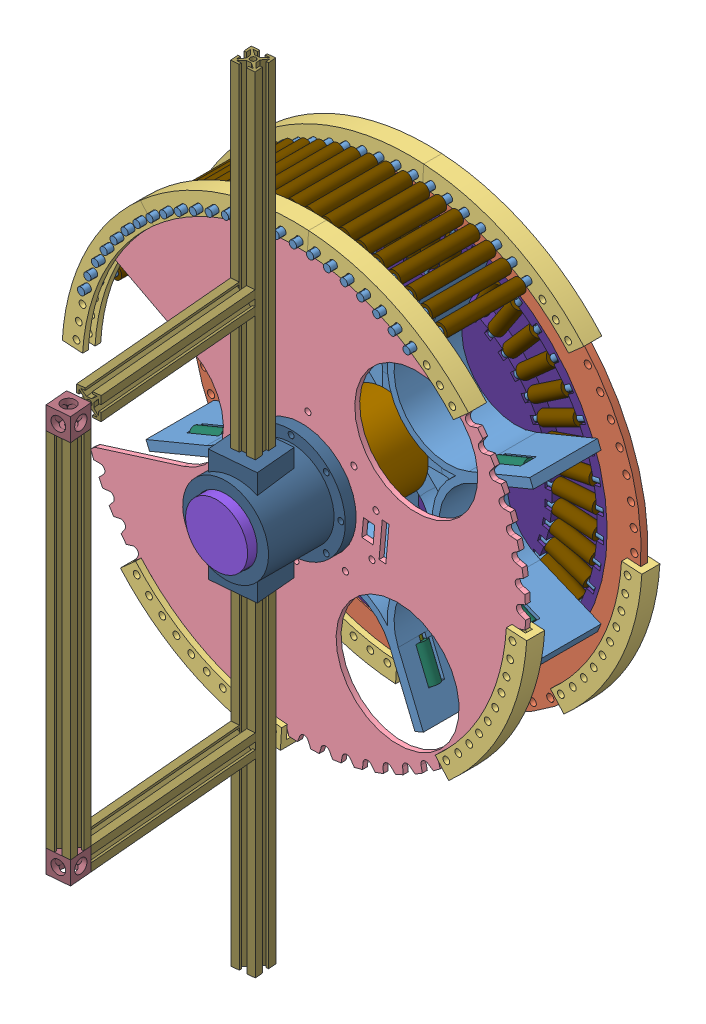
SolidWorks assembly DistributorGrabberAssembly, configuration Default. Lengths in mm.
Overall size (258.72 347.5 175.42).
192 component instances, 20 part files, 82 mates.
Components (placement in the parent):
- DistributorGrabberMainPiece-1: DistributorGrabberMainPiece [Default] at (8.177 183.1473 -41.1858) size (171.5 171.5 30)
- DistributorGrabberStaticCylinder-1: DistributorGrabberStaticCylinder [Default] at (8.177 183.1473 -47.6858) x (-0.932546 -0.361051 0) z (-0.361051 0.932546 0) size (200 3 200)
- ExternalBlockingPiece-1: ExternalBlockingPiece [Default] at (8.177 183.1473 -46.1858) x (-0.748631 -0.662987 0) z (-0.662987 0.748631 0) size (36.53 8 72.83)
- DistributorGrabberStaticTopCylinder-1: DistributorGrabberStaticTopCylinder [Default] at (8.177 183.1473 5.5142) x (-0.088346 -0.99609 0) z (0 0 -1) size (198 187.74 2.2)
- Bearing22mmx7mm-1: Bearing22mmx7mm [Défaut] at (8.177 183.1473 -48.191) x (0 0 -1) z (0.998937 0.04609 0) size (7.02 22 22)
  - AST_Bearings_627H1-1: AST_Bearings_627H1 [Défaut] at origin size (7.02 12.2 12.2)
  - AST_Bearings_627H2-1: AST_Bearings_627H2 [Défaut] at origin size (7.02 22 22)
  - AST_Bearings_627H3-1: AST_Bearings_627H3 [Défaut] at origin size (4.12 17.82 18.09)
- MFA940D1001-1: MFA940D1001 [Default] at (8.177 183.1473 5.3142) x (0 0 -1) z (0 1 0) size (89.5 32 32)
- CentralMotorSupportPart1-1: CentralMotorSupportPart1 [Default] at (8.177 183.1473 5.3142) x (0.707107 -0.707107 0) z (0.707107 0.707107 0) size (48.4 36.5 48.4)
- CentralMotorSupportPart2-1: CentralMotorSupportPart2 [Default] at (8.177 183.1473 5.3142) x (-1 0 0) z (0 1 0) size (48 34 50)
- MotorDistributorGrabberRotor-1: MotorDistributorGrabberRotor [Default] at (8.177 183.1473 -44.1858) size (38 38 20)
- Makerbeam50-1000mm-1: Makerbeam50-1000mm [160mm] at (7.3054 169.3973 26.1553) x (0.996195 0 -0.087156) z (0 -1 0) size (10 10 160)
- Makerbeam50-1000mm-2: Makerbeam50-1000mm [160mm] at (7.3141 196.8973 26.2549) x (-0.996195 0 0.087156) z (0 1 0) size (10 10 160)
- Makerbeam50-1000mm-3: Makerbeam50-1000mm [80mm] at (14.7136 98.3973 110.8319) x (-0.996195 0 0.087156) z (-0.087156 0 -0.996195) size (10 10 80)
- Makerbeam50-1000mm-4: Makerbeam50-1000mm [160mm] at (15.1494 103.3973 115.8128) x (0.996195 0 -0.087156) z (0 1 0) size (10 10 160)
- Makerbeam50-1000mm-5: Makerbeam50-1000mm [75mm] at (7.7499 268.3973 31.2359) x (0.996195 0 -0.087156) z (0.087156 0 0.996195) size (10 10 75)
- MakerBeam-cube-1: MakerBeam-cube [Default] at (15.1494 103.3973 115.8128) x (0.996195 0 -0.087156) z (0 -1 0) size (10 10 10)
- MakerBeam-cube-2: MakerBeam-cube [Default] at (14.7136 268.3973 110.8319) x (0.996195 0 -0.087156) z (0.087156 0 0.996195) size (10 10 10)
- Ball2018-6: Ball2018 [Default] at (-37.5478 134.0815 -22.4358) x (0.994403 0.003773 -0.105582) z (0.105601 -0.005362 0.994394) size (44.5 44.5 44.5)
- RotationCylinder15mm-1: RotationCylinder15mm [Default] at (-65.7215 213.7327 -21.6858) x (0.150802 0.364068 -0.919083) z (0.92388 -0.382683 0) size (6 6 15)
- DistributorGrabberMainPieceThreadedScrew-1: DistributorGrabberMainPieceThreadedScrew [Default] at (-49.0916 206.8444 -21.6858) x (-0.366115 -0.88388 0.29106) z (-0.92388 0.382683 0) size (2.5 2.5 20)
- RotationCylinder15mm-2: RotationCylinder15mm [Default] at (-65.7043 152.5203 -21.6858) x (-0.150802 0.364068 -0.919083) z (0.92388 0.382683 0) size (6 6 15)
- RotationCylinder15mm-3: RotationCylinder15mm [Default] at (-22.4084 109.2488 -21.6858) x (-0.364068 0.150802 -0.919083) z (0.382683 0.92388 0) size (6 6 15)
- RotationCylinder15mm-4: RotationCylinder15mm [Default] at (38.8039 109.266 -21.6858) x (-0.364068 -0.150802 -0.919083) z (-0.382683 0.92388 0) size (6 6 15)
- RotationCylinder15mm-5: RotationCylinder15mm [Default] at (82.0754 152.5619 -21.6858) x (-0.150802 -0.364068 -0.919083) z (-0.92388 0.382683 0) size (6 6 15)
- RotationCylinder15mm-6: RotationCylinder15mm [Default] at (82.0582 213.7742 -21.6858) x (0.150802 -0.364068 -0.919083) z (-0.92388 -0.382683 0) size (6 6 15)
- RotationCylinder15mm-7: RotationCylinder15mm [Default] at (38.7624 257.0457 -21.6858) x (0.364068 -0.150802 -0.919083) z (-0.382683 -0.92388 0) size (6 6 15)
- RotationCylinder15mm-8: RotationCylinder15mm [Default] at (-22.45 257.0285 -21.6858) x (0.364068 0.150802 -0.919083) z (0.382683 -0.92388 0) size (6 6 15)
- DistributorGrabberMainPieceThreadedScrew-2: DistributorGrabberMainPieceThreadedScrew [Default] at (-49.0744 159.4086 -21.6858) x (0.366115 -0.88388 0.29106) z (-0.92388 -0.382683 0) size (2.5 2.5 20)
- DistributorGrabberMainPieceThreadedScrew-3: DistributorGrabberMainPieceThreadedScrew [Default] at (-15.5201 125.8787 -21.6858) x (0.88388 -0.366115 0.29106) z (-0.382683 -0.92388 0) size (2.5 2.5 20)
- DistributorGrabberMainPieceThreadedScrew-4: DistributorGrabberMainPieceThreadedScrew [Default] at (31.9156 125.8959 -21.6858) x (0.88388 0.366115 0.29106) z (0.382683 -0.92388 0) size (2.5 2.5 20)
- DistributorGrabberMainPieceThreadedScrew-5: DistributorGrabberMainPieceThreadedScrew [Default] at (65.4455 159.4502 -21.6858) x (0.366115 0.88388 0.29106) z (0.92388 -0.382683 0) size (2.5 2.5 20)
- DistributorGrabberMainPieceThreadedScrew-6: DistributorGrabberMainPieceThreadedScrew [Default] at (65.4283 206.8859 -21.6858) x (-0.366115 0.88388 0.29106) z (0.92388 0.382683 0) size (2.5 2.5 20)
- DistributorGrabberMainPieceThreadedScrew-7: DistributorGrabberMainPieceThreadedScrew [Default] at (31.8741 240.4159 -21.6858) x (-0.88388 0.366115 0.29106) z (0.382683 0.92388 0) size (2.5 2.5 20)
- DistributorGrabberMainPieceThreadedScrew-8: DistributorGrabberMainPieceThreadedScrew [Default] at (-15.5617 240.3987 -21.6858) x (-0.88388 -0.366115 0.29106) z (-0.382683 0.92388 0) size (2.5 2.5 20)
- DistributorRollingBearSupportWithCylinderSupportAssembly-1: DistributorRollingBearSupportWithCylinderSupportAssembly [Default] at (-21.5454 144.6098 -52.8042) x (-0.894404 -0.447259 0) z (-0.447259 0.894404 0) size (186 10 186)
  - DistributorRollingBearSupportWithCylinderSupport-1: DistributorRollingBearSupportWithCylinderSupport [Default] at (-43.82 -1.3816 21.1745) size (186 9 186)
  - BlockingCylinder-2: BlockingCylinder [18mm] at (35.18 5.6184 21.1745) x (0 0 1) z (-1 0 0) size (6 6 18)
  - BlockingCylinderSupport-1: BlockingCylinderSupport [25mm] at (13.68 5.6184 21.1745) x (0 0 -1) z (1 0 0) size (3.2 3.2 25)
  - BlockingCylinder-3: BlockingCylinder [18mm] at (34.5041 5.6184 31.4861) x (-0.130526 0 0.991445) z (-0.991445 0 -0.130526) size (6 6 18)
  - BlockingCylinder-4: BlockingCylinder [18mm] at (32.4881 5.6184 41.6212) x (-0.258819 0 0.965926) z (-0.965926 0 -0.258819) size (6 6 18)
  - BlockingCylinder-5: BlockingCylinder [18mm] at (29.1665 5.6184 51.4065) x (-0.382683 0 0.92388) z (-0.92388 0 -0.382683) size (6 6 18)
  - BlockingCylinder-6: BlockingCylinder [18mm] at (24.596 5.6184 60.6745) x (-0.5 0 0.866025) z (-0.866025 0 -0.5) size (6 6 18)
  - BlockingCylinder-7: BlockingCylinder [18mm] at (18.8549 5.6184 69.2667) x (-0.608761 0 0.793353) z (-0.793353 0 -0.608761) size (6 6 18)
  - BlockingCylinder-8: BlockingCylinder [18mm] at (12.0414 5.6184 77.0359) x (-0.707107 0 0.707107) z (-0.707107 0 -0.707107) size (6 6 18)
  - BlockingCylinder-9: BlockingCylinder [18mm] at (4.2721 5.6184 83.8494) x (-0.793353 0 0.608761) z (-0.608761 0 -0.793353) size (6 6 18)
  - BlockingCylinder-10: BlockingCylinder [18mm] at (-4.32 5.6184 89.5905) x (-0.866025 0 0.5) z (-0.5 0 -0.866025) size (6 6 18)
  - BlockingCylinder-11: BlockingCylinder [18mm] at (-13.588 5.6184 94.161) x (-0.92388 0 0.382683) z (-0.382683 0 -0.92388) size (6 6 18)
  - BlockingCylinder-12: BlockingCylinder [18mm] at (-23.3733 5.6184 97.4826) x (-0.965926 0 0.258819) z (-0.258819 0 -0.965926) size (6 6 18)
  - BlockingCylinder-13: BlockingCylinder [18mm] at (-33.5085 5.6184 99.4987) x (-0.991445 0 0.130526) z (-0.130526 0 -0.991445) size (6 6 18)
  - BlockingCylinder-14: BlockingCylinder [18mm] at (-43.82 5.6184 100.1745) x (-1 0 0) z (0 0 -1) size (6 6 18)
  - BlockingCylinder-15: BlockingCylinder [18mm] at (-54.1316 5.6184 99.4987) x (-0.991445 0 -0.130526) z (0.130526 0 -0.991445) size (6 6 18)
  - BlockingCylinder-16: BlockingCylinder [18mm] at (-64.2667 5.6184 97.4826) x (-0.965926 0 -0.258819) z (0.258819 0 -0.965926) size (6 6 18)
  - BlockingCylinder-17: BlockingCylinder [18mm] at (-74.052 5.6184 94.161) x (-0.92388 0 -0.382683) z (0.382683 0 -0.92388) size (6 6 18)
  - BlockingCylinder-18: BlockingCylinder [18mm] at (-83.32 5.6184 89.5905) x (-0.866025 0 -0.5) z (0.5 0 -0.866025) size (6 6 18)
  - BlockingCylinder-19: BlockingCylinder [18mm] at (-91.9122 5.6184 83.8494) x (-0.793353 0 -0.608761) z (0.608761 0 -0.793353) size (6 6 18)
  - BlockingCylinder-20: BlockingCylinder [18mm] at (-99.6815 5.6184 77.0359) x (-0.707107 0 -0.707107) z (0.707107 0 -0.707107) size (6 6 18)
  - BlockingCylinder-21: BlockingCylinder [18mm] at (-106.4949 5.6184 69.2667) x (-0.608761 0 -0.793353) z (0.793353 0 -0.608761) size (6 6 18)
  - BlockingCylinder-22: BlockingCylinder [18mm] at (-112.236 5.6184 60.6745) x (-0.5 0 -0.866025) z (0.866025 0 -0.5) size (6 6 18)
  - BlockingCylinder-23: BlockingCylinder [18mm] at (-116.8065 5.6184 51.4065) x (-0.382683 0 -0.92388) z (0.92388 0 -0.382683) size (6 6 18)
  - BlockingCylinder-24: BlockingCylinder [18mm] at (-120.1282 5.6184 41.6212) x (-0.258819 0 -0.965926) z (0.965926 0 -0.258819) size (6 6 18)
  - BlockingCylinder-25: BlockingCylinder [18mm] at (-122.1442 5.6184 31.4861) x (-0.130526 0 -0.991445) z (0.991445 0 -0.130526) size (6 6 18)
  - BlockingCylinder-26: BlockingCylinder [18mm] at (-122.82 5.6184 21.1745) x (0 0 -1) z (1 0 0) size (6 6 18)
  - BlockingCylinder-27: BlockingCylinder [18mm] at (-122.1442 5.6184 10.8629) x (0.130526 0 -0.991445) z (0.991445 0 0.130526) size (6 6 18)
  - BlockingCylinder-28: BlockingCylinder [18mm] at (-120.1282 5.6184 0.7278) x (0.258819 0 -0.965926) z (0.965926 0 0.258819) size (6 6 18)
  - BlockingCylinder-29: BlockingCylinder [18mm] at (-116.8065 5.6184 -9.0575) x (0.382683 0 -0.92388) z (0.92388 0 0.382683) size (6 6 18)
  - BlockingCylinder-30: BlockingCylinder [18mm] at (-112.236 5.6184 -18.3255) x (0.5 0 -0.866025) z (0.866025 0 0.5) size (6 6 18)
  - BlockingCylinder-31: BlockingCylinder [18mm] at (-106.4949 5.6184 -26.9176) x (0.608761 0 -0.793353) z (0.793353 0 0.608761) size (6 6 18)
  - BlockingCylinder-32: BlockingCylinder [18mm] at (-99.6815 5.6184 -34.6869) x (0.707107 0 -0.707107) z (0.707107 0 0.707107) size (6 6 18)
  - BlockingCylinder-33: BlockingCylinder [18mm] at (-91.9122 5.6184 -41.5004) x (0.793353 0 -0.608761) z (0.608761 0 0.793353) size (6 6 18)
  - BlockingCylinder-34: BlockingCylinder [18mm] at (-83.32 5.6184 -47.2415) x (0.866025 0 -0.5) z (0.5 0 0.866025) size (6 6 18)
  - BlockingCylinder-35: BlockingCylinder [18mm] at (-74.052 5.6184 -51.812) x (0.92388 0 -0.382683) z (0.382683 0 0.92388) size (6 6 18)
  - BlockingCylinder-36: BlockingCylinder [18mm] at (-64.2667 5.6184 -55.1336) x (0.965926 0 -0.258819) z (0.258819 0 0.965926) size (6 6 18)
  - BlockingCylinder-37: BlockingCylinder [18mm] at (-54.1316 5.6184 -57.1496) x (0.991445 0 -0.130526) z (0.130526 0 0.991445) size (6 6 18)
  - BlockingCylinder-38: BlockingCylinder [18mm] at (-43.82 5.6184 -57.8255) size (6 6 18)
  - BlockingCylinder-39: BlockingCylinder [18mm] at (-33.5085 5.6184 -57.1496) x (0.991445 0 0.130526) z (-0.130526 0 0.991445) size (6 6 18)
  - BlockingCylinder-40: BlockingCylinder [18mm] at (-23.3733 5.6184 -55.1336) x (0.965926 0 0.258819) z (-0.258819 0 0.965926) size (6 6 18)
  - BlockingCylinder-41: BlockingCylinder [18mm] at (-13.588 5.6184 -51.812) x (0.92388 0 0.382683) z (-0.382683 0 0.92388) size (6 6 18)
  - BlockingCylinder-42: BlockingCylinder [18mm] at (-4.32 5.6184 -47.2415) x (0.866025 0 0.5) z (-0.5 0 0.866025) size (6 6 18)
  - BlockingCylinder-43: BlockingCylinder [18mm] at (4.2721 5.6184 -41.5004) x (0.793353 0 0.608761) z (-0.608761 0 0.793353) size (6 6 18)
  - BlockingCylinder-44: BlockingCylinder [18mm] at (12.0414 5.6184 -34.6869) x (0.707107 0 0.707107) z (-0.707107 0 0.707107) size (6 6 18)
  - BlockingCylinder-45: BlockingCylinder [18mm] at (18.8549 5.6184 -26.9176) x (0.608761 0 0.793353) z (-0.793353 0 0.608761) size (6 6 18)
  - BlockingCylinder-46: BlockingCylinder [18mm] at (24.596 5.6184 -18.3255) x (0.5 0 0.866025) z (-0.866025 0 0.5) size (6 6 18)
  - BlockingCylinder-47: BlockingCylinder [18mm] at (29.1665 5.6184 -9.0575) x (0.382683 0 0.92388) z (-0.92388 0 0.382683) size (6 6 18)
  - BlockingCylinder-48: BlockingCylinder [18mm] at (32.4881 5.6184 0.7278) x (0.258819 0 0.965926) z (-0.965926 0 0.258819) size (6 6 18)
  - BlockingCylinder-49: BlockingCylinder [18mm] at (34.5041 5.6184 10.8629) x (0.130526 0 0.991445) z (-0.991445 0 0.130526) size (6 6 18)
  - BlockingCylinderSupport-2: BlockingCylinderSupport [25mm] at (13.1881 5.6184 28.6798) x (0.130526 0 -0.991445) z (0.991445 0 0.130526) size (3.2 3.2 25)
  - BlockingCylinderSupport-3: BlockingCylinderSupport [25mm] at (11.7207 5.6184 36.0566) x (0.258819 0 -0.965926) z (0.965926 0 0.258819) size (3.2 3.2 25)
  - BlockingCylinderSupport-4: BlockingCylinderSupport [25mm] at (9.303 5.6184 43.1788) x (0.382683 0 -0.92388) z (0.92388 0 0.382683) size (3.2 3.2 25)
  - BlockingCylinderSupport-5: BlockingCylinderSupport [25mm] at (5.9764 5.6184 49.9245) x (0.5 0 -0.866025) z (0.866025 0 0.5) size (3.2 3.2 25)
  - BlockingCylinderSupport-6: BlockingCylinderSupport [25mm] at (1.7978 5.6184 56.1783) x (0.608761 0 -0.793353) z (0.793353 0 0.608761) size (3.2 3.2 25)
  - BlockingCylinderSupport-7: BlockingCylinderSupport [25mm] at (-3.1614 5.6184 61.8331) x (0.707107 0 -0.707107) z (0.707107 0 0.707107) size (3.2 3.2 25)
  - BlockingCylinderSupport-8: BlockingCylinderSupport [25mm] at (-8.8162 5.6184 66.7923) x (0.793353 0 -0.608761) z (0.608761 0 0.793353) size (3.2 3.2 25)
  - BlockingCylinderSupport-9: BlockingCylinderSupport [25mm] at (-15.07 5.6184 70.971) x (0.866025 0 -0.5) z (0.5 0 0.866025) size (3.2 3.2 25)
  - BlockingCylinderSupport-10: BlockingCylinderSupport [25mm] at (-21.8157 5.6184 74.2976) x (0.92388 0 -0.382683) z (0.382683 0 0.92388) size (3.2 3.2 25)
  - BlockingCylinderSupport-11: BlockingCylinderSupport [25mm] at (-28.9379 5.6184 76.7152) x (0.965926 0 -0.258819) z (0.258819 0 0.965926) size (3.2 3.2 25)
  - BlockingCylinderSupport-12: BlockingCylinderSupport [25mm] at (-36.3148 5.6184 78.1826) x (0.991445 0 -0.130526) z (0.130526 0 0.991445) size (3.2 3.2 25)
  - BlockingCylinderSupport-13: BlockingCylinderSupport [25mm] at (-43.82 5.6184 78.6745) size (3.2 3.2 25)
  - BlockingCylinderSupport-14: BlockingCylinderSupport [25mm] at (-51.3253 5.6184 78.1826) x (0.991445 0 0.130526) z (-0.130526 0 0.991445) size (3.2 3.2 25)
  - BlockingCylinderSupport-15: BlockingCylinderSupport [25mm] at (-58.7021 5.6184 76.7152) x (0.965926 0 0.258819) z (-0.258819 0 0.965926) size (3.2 3.2 25)
  - BlockingCylinderSupport-16: BlockingCylinderSupport [25mm] at (-65.8243 5.6184 74.2976) x (0.92388 0 0.382683) z (-0.382683 0 0.92388) size (3.2 3.2 25)
  - BlockingCylinderSupport-17: BlockingCylinderSupport [25mm] at (-72.57 5.6184 70.971) x (0.866025 0 0.5) z (-0.5 0 0.866025) size (3.2 3.2 25)
  - BlockingCylinderSupport-18: BlockingCylinderSupport [25mm] at (-78.8238 5.6184 66.7923) x (0.793353 0 0.608761) z (-0.608761 0 0.793353) size (3.2 3.2 25)
  - BlockingCylinderSupport-19: BlockingCylinderSupport [25mm] at (-84.4787 5.6184 61.8331) x (0.707107 0 0.707107) z (-0.707107 0 0.707107) size (3.2 3.2 25)
  - BlockingCylinderSupport-20: BlockingCylinderSupport [25mm] at (-89.4378 5.6184 56.1783) x (0.608761 0 0.793353) z (-0.793353 0 0.608761) size (3.2 3.2 25)
  - BlockingCylinderSupport-21: BlockingCylinderSupport [25mm] at (-93.6165 5.6184 49.9245) x (0.5 0 0.866025) z (-0.866025 0 0.5) size (3.2 3.2 25)
  - BlockingCylinderSupport-22: BlockingCylinderSupport [25mm] at (-96.9431 5.6184 43.1788) x (0.382683 0 0.92388) z (-0.92388 0 0.382683) size (3.2 3.2 25)
  - BlockingCylinderSupport-23: BlockingCylinderSupport [25mm] at (-99.3608 5.6184 36.0566) x (0.258819 0 0.965926) z (-0.965926 0 0.258819) size (3.2 3.2 25)
  - BlockingCylinderSupport-24: BlockingCylinderSupport [25mm] at (-100.8281 5.6184 28.6798) x (0.130526 0 0.991445) z (-0.991445 0 0.130526) size (3.2 3.2 25)
  - BlockingCylinderSupport-25: BlockingCylinderSupport [25mm] at (-101.32 5.6184 21.1745) x (0 0 1) z (-1 0 0) size (3.2 3.2 25)
  - BlockingCylinderSupport-26: BlockingCylinderSupport [25mm] at (-100.8281 5.6184 13.6693) x (-0.130526 0 0.991445) z (-0.991445 0 -0.130526) size (3.2 3.2 25)
  - BlockingCylinderSupport-27: BlockingCylinderSupport [25mm] at (-99.3608 5.6184 6.2924) x (-0.258819 0 0.965926) z (-0.965926 0 -0.258819) size (3.2 3.2 25)
  - BlockingCylinderSupport-28: BlockingCylinderSupport [25mm] at (-96.9431 5.6184 -0.8298) x (-0.382683 0 0.92388) z (-0.92388 0 -0.382683) size (3.2 3.2 25)
  - BlockingCylinderSupport-29: BlockingCylinderSupport [25mm] at (-93.6165 5.6184 -7.5755) x (-0.5 0 0.866025) z (-0.866025 0 -0.5) size (3.2 3.2 25)
  - BlockingCylinderSupport-30: BlockingCylinderSupport [25mm] at (-89.4378 5.6184 -13.8293) x (-0.608761 0 0.793353) z (-0.793353 0 -0.608761) size (3.2 3.2 25)
  - BlockingCylinderSupport-31: BlockingCylinderSupport [25mm] at (-84.4787 5.6184 -19.4841) x (-0.707107 0 0.707107) z (-0.707107 0 -0.707107) size (3.2 3.2 25)
  - BlockingCylinderSupport-32: BlockingCylinderSupport [25mm] at (-78.8238 5.6184 -24.4433) x (-0.793353 0 0.608761) z (-0.608761 0 -0.793353) size (3.2 3.2 25)
  - BlockingCylinderSupport-33: BlockingCylinderSupport [25mm] at (-72.57 5.6184 -28.622) x (-0.866025 0 0.5) z (-0.5 0 -0.866025) size (3.2 3.2 25)
  - BlockingCylinderSupport-34: BlockingCylinderSupport [25mm] at (-65.8243 5.6184 -31.9486) x (-0.92388 0 0.382683) z (-0.382683 0 -0.92388) size (3.2 3.2 25)
  - BlockingCylinderSupport-35: BlockingCylinderSupport [25mm] at (-58.7021 5.6184 -34.3662) x (-0.965926 0 0.258819) z (-0.258819 0 -0.965926) size (3.2 3.2 25)
  - BlockingCylinderSupport-36: BlockingCylinderSupport [25mm] at (-51.3253 5.6184 -35.8336) x (-0.991445 0 0.130526) z (-0.130526 0 -0.991445) size (3.2 3.2 25)
  - BlockingCylinderSupport-37: BlockingCylinderSupport [25mm] at (-43.82 5.6184 -36.3255) x (-1 0 0) z (0 0 -1) size (3.2 3.2 25)
  - BlockingCylinderSupport-38: BlockingCylinderSupport [25mm] at (-36.3148 5.6184 -35.8336) x (-0.991445 0 -0.130526) z (0.130526 0 -0.991445) size (3.2 3.2 25)
  - BlockingCylinderSupport-39: BlockingCylinderSupport [25mm] at (-28.9379 5.6184 -34.3662) x (-0.965926 0 -0.258819) z (0.258819 0 -0.965926) size (3.2 3.2 25)
  - BlockingCylinderSupport-40: BlockingCylinderSupport [25mm] at (-21.8157 5.6184 -31.9486) x (-0.92388 0 -0.382683) z (0.382683 0 -0.92388) size (3.2 3.2 25)
  - BlockingCylinderSupport-41: BlockingCylinderSupport [25mm] at (-15.07 5.6184 -28.622) x (-0.866025 0 -0.5) z (0.5 0 -0.866025) size (3.2 3.2 25)
  - BlockingCylinderSupport-42: BlockingCylinderSupport [25mm] at (-8.8162 5.6184 -24.4433) x (-0.793353 0 -0.608761) z (0.608761 0 -0.793353) size (3.2 3.2 25)
  - BlockingCylinderSupport-43: BlockingCylinderSupport [25mm] at (-3.1614 5.6184 -19.4841) x (-0.707107 0 -0.707107) z (0.707107 0 -0.707107) size (3.2 3.2 25)
  - BlockingCylinderSupport-44: BlockingCylinderSupport [25mm] at (1.7978 5.6184 -13.8293) x (-0.608761 0 -0.793353) z (0.793353 0 -0.608761) size (3.2 3.2 25)
  - BlockingCylinderSupport-45: BlockingCylinderSupport [25mm] at (5.9764 5.6184 -7.5755) x (-0.5 0 -0.866025) z (0.866025 0 -0.5) size (3.2 3.2 25)
  - BlockingCylinderSupport-46: BlockingCylinderSupport [25mm] at (9.303 5.6184 -0.8298) x (-0.382683 0 -0.92388) z (0.92388 0 -0.382683) size (3.2 3.2 25)
  - BlockingCylinderSupport-47: BlockingCylinderSupport [25mm] at (11.7207 5.6184 6.2924) x (-0.258819 0 -0.965926) z (0.965926 0 -0.258819) size (3.2 3.2 25)
  - BlockingCylinderSupport-48: BlockingCylinderSupport [25mm] at (13.1881 5.6184 13.6693) x (-0.130526 0 -0.991445) z (0.991445 0 -0.130526) size (3.2 3.2 25)
- ExternalBlockingPiece-2: ExternalBlockingPiece [Default] at (8.177 183.1473 -46.1858) x (-0.060559 -0.998165 0) z (-0.998165 0.060559 0) size (36.53 8 72.83)
- ExternalBlockingPiece-3: ExternalBlockingPiece [Default] at (8.177 183.1473 -46.1858) x (0.662987 -0.748631 0) z (-0.748631 -0.662987 0) size (36.53 8 72.83)
- ExternalBlockingPiece-4: ExternalBlockingPiece [Default] at (8.177 183.1473 4.8142) x (-0.060559 -0.998165 0) z (0.998165 -0.060559 0) size (36.53 8 72.83)
- ExternalBlockingPiece-5: ExternalBlockingPiece [Default] at (8.177 183.1473 4.8142) x (0.662987 -0.748631 0) z (0.748631 0.662987 0) size (36.53 8 72.83)
- ExternalBlockingPiece-6: ExternalBlockingPiece [Default] at (8.177 183.1473 4.8142) x (0.998165 -0.060559 0) z (0.060559 0.998165 0) size (36.53 8 72.83)
- ExternalBlockingPiece-8: ExternalBlockingPiece [Default] at (8.177 183.1473 -46.1858) x (-0.662987 0.748631 0) z (0.748631 0.662987 0) size (36.53 8 72.83)
- ExternalBlockingPiece-9: ExternalBlockingPiece [Default] at (8.177 183.1473 -46.1858) x (0.748631 0.662987 0) z (0.662987 -0.748631 0) size (36.53 8 72.83)
- ExternalBlockingPiece-10: ExternalBlockingPiece [Default] at (8.177 183.1473 4.8142) x (-0.998165 0.060559 0) z (-0.060559 -0.998165 0) size (36.53 8 72.83)
- ExternalBlockingPiece-11: ExternalBlockingPiece [Default] at (8.177 183.1473 4.8142) x (0.060559 0.998165 0) z (-0.998165 0.060559 0) size (36.53 8 72.83)
- Pièce1^DistributorGrabberAssembly-1: Pièce1^DistributorGrabberAssembly [Default] at origin (virtual)
- BlockingCylinderSupport-1: BlockingCylinderSupport [65mm] at (60.7728 264.6499 -53.1858) size (3.2 3.2 65)
- BlockingCylinder-1: BlockingCylinder [35mm] at (60.7728 264.6499 -38.1858) x (0.359506 0.933143 0) z (0 0 1) size (6 6 35)
- BlockingCylinderSupport-2: BlockingCylinderSupport [65mm] at (54.2161 268.5252 -53.1858) x (0.996917 0.078459 0) z (0 0 1) size (3.2 3.2 65)
- BlockingCylinderSupport-3: BlockingCylinderSupport [65mm] at (47.3755 271.8742 -53.1858) x (0.987688 0.156434 0) z (0 0 1) size (3.2 3.2 65)
- BlockingCylinderSupport-4: BlockingCylinderSupport [65mm] at (40.2932 274.6762 -53.1858) x (0.97237 0.233445 0) z (0 0 1) size (3.2 3.2 65)
- BlockingCylinderSupport-5: BlockingCylinderSupport [65mm] at (33.0129 276.9139 -53.1858) x (0.951057 0.309017 0) z (0 0 1) size (3.2 3.2 65)
- BlockingCylinderSupport-6: BlockingCylinderSupport [65mm] at (25.5795 278.5734 -53.1858) x (0.92388 0.382683 0) z (0 0 1) size (3.2 3.2 65)
- BlockingCylinderSupport-7: BlockingCylinderSupport [65mm] at (18.0388 279.6446 -53.1858) x (0.891007 0.45399 0) z (0 0 1) size (3.2 3.2 65)
- BlockingCylinderSupport-8: BlockingCylinderSupport [65mm] at (10.4373 280.1209 -53.1858) x (0.85264 0.522499 0) z (0 0 1) size (3.2 3.2 65)
- BlockingCylinderSupport-9: BlockingCylinderSupport [65mm] at (2.8219 279.9993 -53.1858) x (0.809017 0.587785 0) z (0 0 1) size (3.2 3.2 65)
- BlockingCylinderSupport-10: BlockingCylinderSupport [65mm] at (-4.7605 279.2806 -53.1858) x (0.760406 0.649448 0) z (0 0 1) size (3.2 3.2 65)
- BlockingCylinderSupport-11: BlockingCylinderSupport [65mm] at (-12.2632 277.9692 -53.1858) x (0.707107 0.707107 0) z (0 0 1) size (3.2 3.2 65)
- BlockingCylinderSupport-12: BlockingCylinderSupport [65mm] at (-19.6398 276.0732 -53.1858) x (0.649448 0.760406 0) z (0 0 1) size (3.2 3.2 65)
- BlockingCylinderSupport-13: BlockingCylinderSupport [65mm] at (-26.845 273.6043 -53.1858) x (0.587785 0.809017 0) z (0 0 1) size (3.2 3.2 65)
- BlockingCylinderSupport-14: BlockingCylinderSupport [65mm] at (-33.8342 270.5776 -53.1858) x (0.522499 0.85264 0) z (0 0 1) size (3.2 3.2 65)
- BlockingCylinderSupport-15: BlockingCylinderSupport [65mm] at (-40.5644 267.0119 -53.1858) x (0.45399 0.891007 0) z (0 0 1) size (3.2 3.2 65)
- BlockingCylinderSupport-16: BlockingCylinderSupport [65mm] at (-46.9941 262.9292 -53.1858) x (0.382683 0.92388 0) z (0 0 1) size (3.2 3.2 65)
- BlockingCylinderSupport-17: BlockingCylinderSupport [65mm] at (-53.0836 258.3546 -53.1858) x (0.309017 0.951057 0) z (0 0 1) size (3.2 3.2 65)
- BlockingCylinderSupport-18: BlockingCylinderSupport [65mm] at (-58.7955 253.3163 -53.1858) x (0.233445 0.97237 0) z (0 0 1) size (3.2 3.2 65)
- BlockingCylinderSupport-19: BlockingCylinderSupport [65mm] at (-64.0944 247.8454 -53.1858) x (0.156434 0.987688 0) z (0 0 1) size (3.2 3.2 65)
- BlockingCylinderSupport-20: BlockingCylinderSupport [65mm] at (-68.9478 241.9756 -53.1858) x (0.078459 0.996917 0) z (0 0 1) size (3.2 3.2 65)
- BlockingCylinderSupport-21: BlockingCylinderSupport [65mm] at (-73.3256 235.7431 -53.1858) x (0 1 0) z (0 0 1) size (3.2 3.2 65)
- BlockingCylinderSupport-22: BlockingCylinderSupport [65mm] at (-77.201 229.1864 -53.1858) x (-0.078459 0.996917 0) z (0 0 1) size (3.2 3.2 65)
- BlockingCylinderSupport-23: BlockingCylinderSupport [65mm] at (-80.55 222.3458 -53.1858) x (-0.156434 0.987688 0) z (0 0 1) size (3.2 3.2 65)
- BlockingCylinderSupport-24: BlockingCylinderSupport [65mm] at (-83.352 215.2635 -53.1858) x (-0.233445 0.97237 0) z (0 0 1) size (3.2 3.2 65)
- BlockingCylinder-2: BlockingCylinder [35mm] at (54.2161 268.5252 -38.1858) x (0.285184 0.958473 0) z (0 0 1) size (6 6 35)
- BlockingCylinder-3: BlockingCylinder [35mm] at (47.3755 271.8742 -38.1858) x (0.209104 0.977893 0) z (0 0 1) size (6 6 35)
- BlockingCylinder-4: BlockingCylinder [35mm] at (40.2932 274.6762 -38.1858) x (0.131735 0.991285 0) z (0 0 1) size (6 6 35)
- BlockingCylinder-5: BlockingCylinder [35mm] at (33.0129 276.9139 -38.1858) x (0.053553 0.998565 0) z (0 0 1) size (6 6 35)
- BlockingCylinder-6: BlockingCylinder [35mm] at (25.5795 278.5734 -38.1858) x (-0.024958 0.999688 0) z (0 0 1) size (6 6 35)
- BlockingCylinder-7: BlockingCylinder [35mm] at (18.0388 279.6446 -38.1858) x (-0.103316 0.994649 0) z (0 0 1) size (6 6 35)
- BlockingCylinder-8: BlockingCylinder [35mm] at (10.4373 280.1209 -38.1858) x (-0.181037 0.983476 0) z (0 0 1) size (6 6 35)
- BlockingCylinder-9: BlockingCylinder [35mm] at (2.8219 279.9993 -38.1858) x (-0.257641 0.966241 0) z (0 0 1) size (6 6 35)
- BlockingCylinder-10: BlockingCylinder [35mm] at (-4.7605 279.2806 -38.1858) x (-0.332657 0.943048 0) z (0 0 1) size (6 6 35)
- BlockingCylinder-11: BlockingCylinder [35mm] at (-12.2632 277.9692 -38.1858) x (-0.405623 0.914041 0) z (0 0 1) size (6 6 35)
- BlockingCylinder-12: BlockingCylinder [35mm] at (-19.6398 276.0732 -38.1858) x (-0.476087 0.879398 0) z (0 0 1) size (6 6 35)
- BlockingCylinder-13: BlockingCylinder [35mm] at (-26.845 273.6043 -38.1858) x (-0.543616 0.839334 0) z (0 0 1) size (6 6 35)
- BlockingCylinder-14: BlockingCylinder [35mm] at (-33.8342 270.5776 -38.1858) x (-0.607794 0.794095 0) z (0 0 1) size (6 6 35)
- BlockingCylinder-15: BlockingCylinder [35mm] at (-40.5644 267.0119 -38.1858) x (-0.668224 0.74396 0) z (0 0 1) size (6 6 35)
- BlockingCylinder-16: BlockingCylinder [35mm] at (-46.9941 262.9292 -38.1858) x (-0.724535 0.689238 0) z (0 0 1) size (6 6 35)
- BlockingCylinder-17: BlockingCylinder [35mm] at (-53.0836 258.3546 -38.1858) x (-0.776378 0.630267 0) z (0 0 1) size (6 6 35)
- BlockingCylinder-18: BlockingCylinder [35mm] at (-58.7955 253.3163 -38.1858) x (-0.823435 0.56741 0) z (0 0 1) size (6 6 35)
- BlockingCylinder-19: BlockingCylinder [35mm] at (-64.0944 247.8454 -38.1858) x (-0.865415 0.501055 0) z (0 0 1) size (6 6 35)
- BlockingCylinder-20: BlockingCylinder [35mm] at (-68.9478 241.9756 -38.1858) x (-0.90206 0.431611 0) z (0 0 1) size (6 6 35)
- BlockingCylinder-21: BlockingCylinder [35mm] at (-73.3256 235.7431 -38.1858) x (-0.933143 0.359506 0) z (0 0 1) size (6 6 35)
- BlockingCylinder-22: BlockingCylinder [35mm] at (-77.201 229.1864 -38.1858) x (-0.958473 0.285184 0) z (0 0 1) size (6 6 35)
- BlockingCylinder-23: BlockingCylinder [35mm] at (-80.55 222.3458 -38.1858) x (-0.977893 0.209104 0) z (0 0 1) size (6 6 35)
- BlockingCylinder-24: BlockingCylinder [35mm] at (-83.352 215.2635 -38.1858) x (-0.991285 0.131735 0) z (0 0 1) size (6 6 35)
Mates (geometry in assembly coordinates):
- Coaxiale6: concentric: cylinder of DistributorGrabberStaticCylinder-1 through (8.177 183.1473 -47.6858) axis (0 0 1) radius 85; cylinder of DistributorGrabberStaticTopCylinder-1 through (8.177 183.1473 3.3142) axis (0 0 1) radius 24.1
- Coaxiale7: concentric anti-aligned: cylinder of DistributorGrabberStaticCylinder-1 through (8.177 183.1473 -47.6858) axis (0 0 1) radius 85; cylinder of Bearing22mmx7mm-1/AST_Bearings_627H2-1 through (8.177 183.1473 -45.0363) axis (0 0 -1) radius 10.9982
- Coïncidente6: coincident aligned: plane of DistributorGrabberStaticCylinder-1 through (-85.0777 147.0422 -44.6858) normal (0 0 1); plane of Bearing22mmx7mm-1/AST_Bearings_627H2-1 through (18.7326 194.7197 -44.6858) normal (0 0 1)
- Coaxiale8: concentric anti-aligned: cylinder of Bearing22mmx7mm-1/AST_Bearings_627H2-1 through (8.177 183.1473 -45.0363) axis (0 0 -1) radius 10.9982; cylinder of ? through (8.177 183.1473 -47.7858) axis (0 0 1) radius 11
- Coïncidente7: coincident anti-aligned: plane of DistributorGrabberStaticCylinder-1 through (8.177 183.1473 -47.6858) normal (0 0 -1); plane of ? through (19.1767 183.2249 -47.6858) normal (0 0 1)
- Coaxiale10: concentric aligned: cylinder of MFA940D1001-1 through (8.177 183.1473 47.7892) axis (0 0 1) radius 16; cylinder of CentralMotorSupportPart1-1 through (8.177 183.1473 7.1392) axis (0 0 1) radius 16.2
- Coaxiale11: concentric aligned: circle of MFA940D1001-1; cylinder of CentralMotorSupportPart1-1 through (-1.0154 192.3397 -31.1858) axis (0 0 -1) radius 1.6
- Coïncidente10: coincident anti-aligned: plane of MFA940D1001-1 through (-7.823 183.1473 -28.1858) normal (0 0 -1); plane of CentralMotorSupportPart1-1 through (19.6321 171.6921 -28.1858) normal (0 0 1)
- Coaxiale12: concentric anti-aligned: cylinder of MFA940D1001-1 through (8.177 183.1473 47.7892) axis (0 0 1) radius 13.75; cylinder of CentralMotorSupportPart2-1 through (8.177 183.1473 3.4892) axis (0 0 -1) radius 14
- Coaxiale13: concentric anti-aligned: cylinder of CentralMotorSupportPart1-1 through (-7.3794 198.7036 -31.1858) axis (0 0 1) radius 1.3; cylinder of CentralMotorSupportPart2-1 through (-7.3794 198.7036 39.3142) axis (0 0 -1) radius 1.3
- Coïncidente11: coincident anti-aligned: plane of CentralMotorSupportPart1-1 through (25.2889 166.0353 5.3142) normal (0 0 1); plane of CentralMotorSupportPart2-1 through (-15.823 183.1473 5.3142) normal (0 0 -1)
- Coaxiale14: concentric anti-aligned: cylinder of MFA940D1001-1 through (8.177 183.1473 47.7892) axis (0 0 1) radius 3; cylinder of MotorDistributorGrabberRotor-1 through (8.177 183.1473 -31.1858) axis (0 0 -1) radius 3.1
- Coïncidente12: coincident anti-aligned: plane of MFA940D1001-1 through (-1.823 183.1473 -31.1858) normal (0 0 -1); plane of MotorDistributorGrabberRotor-1 through (8.177 183.1473 -31.1858) normal (0 0 1)
- Coïncidente13: coincident anti-aligned: plane of DistributorGrabberMainPiece-1 through (76.177 183.1473 -41.1858) normal (0 0 -1); plane of MotorDistributorGrabberRotor-1 through (8.177 183.1473 -41.1858) normal (0 0 1)
- Coaxiale15: concentric anti-aligned: cylinder of DistributorGrabberMainPiece-1 through (8.177 183.1473 -41.1858) axis (0 0 1) radius 6.5; cylinder of MotorDistributorGrabberRotor-1 through (8.177 183.1473 -31.1858) axis (0 0 -1) radius 8.925
- Coaxiale16: concentric anti-aligned: cylinder of Bearing22mmx7mm-1/AST_Bearings_627H1-1 through (8.177 183.1473 -45.0363) axis (0 0 -1) radius 3.5052; cylinder of MotorDistributorGrabberRotor-1 through (8.177 183.1473 -51.1858) axis (0 0 1) radius 4
- Coïncidente14: coincident anti-aligned: plane of Bearing22mmx7mm-1/AST_Bearings_627H1-1 through (14.2267 189.7756 -44.6858) normal (0 0 1); plane of MotorDistributorGrabberRotor-1 through (8.177 183.1473 -44.6858) normal (0 0 -1)
- Coaxiale17: concentric anti-aligned: cylinder of DistributorGrabberStaticCylinder-1 through (8.177 183.1473 7.3142) axis (0 0 1) radius 100; cylinder of ExternalBlockingPiece-1 through (8.177 183.1473 -101.1858) axis (0 0 -1) radius 103
- Coïncidente15: coincident anti-aligned: plane of DistributorGrabberStaticCylinder-1 through (-85.0777 147.0422 -44.6858) normal (0 0 1); plane of ExternalBlockingPiece-1 through (14.2328 282.9637 -44.6858) normal (0 0 -1)
- Distance1: distance = 48 mm anti-aligned: plane of DistributorGrabberStaticCylinder-1 through (-85.0777 147.0422 -44.6858) normal (0 0 1); plane of DistributorGrabberStaticTopCylinder-1 through (8.177 183.1473 3.3142) normal (0 0 -1)
- Coïncidente16: coincident anti-aligned: plane of CentralMotorSupportPart2-1 through (1.8886 158.1473 21.6101) normal (0.087156 0 0.996195); plane of Makerbeam50-1000mm-1 through (5.3753 9.3973 21.3051) normal (-0.087156 0 -0.996195)
- Coïncidente17: coincident anti-aligned: plane of CentralMotorSupportPart2-1 through (2.2024 158.1473 25.1964) normal (0.996195 0 -0.087156); plane of Makerbeam50-1000mm-1 through (1.8886 9.3973 21.6101) normal (-0.996195 0 0.087156)
- Tangent1: tangent anti-aligned: cylinder of MFA940D1001-1 through (8.177 183.1473 47.7892) axis (0 0 1) radius 13.75; plane of Makerbeam50-1000mm-1 through (7.3054 169.3973 26.1553) normal (0 1 0)
- Coïncidente19: coincident anti-aligned: plane of CentralMotorSupportPart2-1 through (6.3552 208.1473 31.3579) normal (-0.087156 0 -0.996195); plane of Makerbeam50-1000mm-2 through (12.7309 356.8973 30.8001) normal (0.087156 0 0.996195)
- Coïncidente20: coincident anti-aligned: plane of CentralMotorSupportPart2-1 through (2.7689 208.1473 31.6717) normal (0.996195 0 -0.087156); plane of Makerbeam50-1000mm-2 through (2.7689 356.8973 31.6717) normal (-0.996195 0 0.087156)
- Tangent3: tangent anti-aligned: cylinder of MFA940D1001-1 through (8.177 183.1473 47.7892) axis (0 0 1) radius 13.75; plane of Makerbeam50-1000mm-2 through (7.3141 196.8973 26.2549) normal (0 -1 0)
- Coïncidente21: coincident anti-aligned: plane of Makerbeam50-1000mm-1 through (9.2355 9.3973 31.0056) normal (0.087156 0 0.996195); plane of Makerbeam50-1000mm-3 through (7.7412 98.3973 31.1363) normal (-0.087156 0 -0.996195)
- Coïncidente22: coincident aligned: plane of Makerbeam50-1000mm-1 through (1.8886 9.3973 21.6101) normal (-0.996195 0 0.087156); plane of Makerbeam50-1000mm-3 through (2.7602 96.8973 31.5721) normal (-0.996195 0 0.087156)
- Coïncidente23: coincident anti-aligned: plane of Makerbeam50-1000mm-3 through (14.7136 98.3973 110.8319) normal (0.087156 0 0.996195); plane of Makerbeam50-1000mm-4 through (9.7327 263.3973 111.2676) normal (-0.087156 0 -0.996195)
- Coïncidente24: coincident aligned: plane of Makerbeam50-1000mm-3 through (2.7602 96.8973 31.5721) normal (-0.996195 0 0.087156); plane of Makerbeam50-1000mm-4 through (10.0377 263.3973 114.7543) normal (-0.996195 0 0.087156)
- Coïncidente25: coincident anti-aligned: plane of Makerbeam50-1000mm-2 through (12.7309 356.8973 30.8001) normal (0.087156 0 0.996195); plane of Makerbeam50-1000mm-5 through (7.7499 268.3973 31.2359) normal (-0.087156 0 -0.996195)
- Coïncidente26: coincident aligned: plane of Makerbeam50-1000mm-2 through (2.7689 356.8973 31.6717) normal (-0.996195 0 0.087156); plane of Makerbeam50-1000mm-5 through (9.3056 263.3973 106.3863) normal (-0.996195 0 0.087156)
- Coïncidente27: coincident anti-aligned: plane of Makerbeam50-1000mm-2 through (2.7689 356.8973 31.6717) normal (-0.996195 0 0.087156); plane of ? through (2.7689 158.1473 31.6717) normal (0.996195 0 -0.087156)
- Coïncidente28: coincident aligned: plane of Makerbeam50-1000mm-2 through (6.2556 356.8973 31.3666) normal (0.087156 0 0.996195); plane of ? through (2.7689 158.1473 31.6717) normal (0.087156 0 0.996195)
- Tangent4: tangent aligned: cylinder of ? through (-34.9352 278.9549 29.9513) axis (-0.086824 -0.996195 0.007596) radius 25; sphere of ?
- Coaxiale18: concentric aligned: cylinder of Makerbeam50-1000mm-4 through (15.1494 263.3973 115.8128) axis (0 -1 0) radius 1.25; cylinder of MakerBeam-cube-1 through (15.1494 93.3973 115.8128) axis (0 -1 0) radius 1.25
- Coïncidente29: coincident anti-aligned: plane of Makerbeam50-1000mm-4 through (15.1494 103.3973 115.8128) normal (0 -1 0); plane of MakerBeam-cube-1 through (15.1494 103.3973 115.8128) normal (0 1 0)
- Coïncidente30: coincident aligned: plane of Makerbeam50-1000mm-4 through (10.0377 263.3973 114.7543) normal (-0.996195 0 0.087156); plane of MakerBeam-cube-1 through (9.7327 93.3973 111.2676) normal (-0.996195 0 0.087156)
- Coïncidente31: coincident aligned: plane of Makerbeam50-1000mm-3 through (6.2469 93.3973 31.267) normal (0 -1 0); plane of MakerBeam-cube-1 through (15.1494 93.3973 115.8128) normal (0 -1 0)
- Coaxiale19: concentric aligned: cylinder of Makerbeam50-1000mm-4 through (15.1494 263.3973 115.8128) axis (0 -1 0) radius 1.25; cylinder of MakerBeam-cube-2 through (15.1494 263.3973 115.8128) axis (0 -1 0) radius 1.25
- Coïncidente32: coincident aligned: plane of Makerbeam50-1000mm-4 through (10.0377 263.3973 114.7543) normal (-0.996195 0 0.087156); plane of MakerBeam-cube-2 through (10.6042 263.3973 121.2296) normal (-0.996195 0 0.087156)
- Coïncidente33: coincident aligned: plane of Makerbeam50-1000mm-5 through (15.7809 273.3973 105.8198) normal (0 1 0); plane of MakerBeam-cube-2 through (20.5662 273.3973 120.358) normal (0 1 0)
- Coïncidente34: coincident anti-aligned: plane of Makerbeam50-1000mm-4 through (15.1494 263.3973 115.8128) normal (0 1 0); plane of MakerBeam-cube-2 through (20.5662 263.3973 120.358) normal (0 -1 0)
- Coïncidente35: coincident aligned: plane of CentralMotorSupportPart2-1 through (8.177 158.1473 5.3142) normal (0 -1 0); plane of ? through (2.7689 158.1473 31.6717) normal (0 -1 0)
- Tangent9: tangent: plane of ?; sphere of ?
- Tangent12: tangent: cylinder of ? through (17.4259 302.2804 122.4623) axis (-0.236079 0.105559 -0.965983) radius 47.3283; sphere of ?
- Coaxiale21: concentric anti-aligned: cylinder of ? through (-3.6877 224.3498 3.7675) axis (0.087156 0 0.996195) radius 1.3; cylinder of ? through (-0.9544 224.3498 35.0089) axis (-0.087156 0 -0.996195) radius 1.6
- Coaxiale22: concentric anti-aligned: cylinder of ? through (-3.6877 214.3498 3.7675) axis (0.087156 0 0.996195) radius 1.3; cylinder of ? through (-0.9544 214.3498 35.0089) axis (-0.087156 0 -0.996195) radius 1.6
- Coïncidente36: coincident anti-aligned: plane of ? through (2.7689 158.1473 31.6717) normal (0.087156 0 0.996195); plane of ? through (-6.1968 229.3498 32.4561) normal (-0.087156 0 -0.996195)
- Tangent13: tangent anti-aligned: plane of DistributorGrabberStaticCylinder-1 through (-85.0777 147.0422 -44.6858) normal (0 0 1); sphere of Ball2018-6
- Coaxiale23: concentric anti-aligned: cylinder of DistributorGrabberMainPiece-1 through (-49.0916 206.8444 -21.6858) axis (-0.92388 0.382683 0) radius 1.3; cylinder of DistributorGrabberMainPieceThreadedScrew-1 through (-67.5692 214.498 -21.6858) axis (0.92388 -0.382683 0) radius 1.25
- Coïncidente37: coincident anti-aligned: plane of DistributorGrabberMainPiece-1 through (-49.0916 206.8444 -21.6858) normal (-0.92388 0.382683 0); plane of DistributorGrabberMainPieceThreadedScrew-1 through (-49.0916 206.8444 -21.6858) normal (0.92388 -0.382683 0)
- Coaxiale24: concentric anti-aligned: cylinder of RotationCylinder15mm-1 through (-51.8633 207.9924 -21.6858) axis (-0.92388 0.382683 0) radius 1.5; cylinder of DistributorGrabberMainPieceThreadedScrew-1 through (-67.5692 214.498 -21.6858) axis (0.92388 -0.382683 0) radius 1.25
- Coïncidente38: coincident anti-aligned: plane of DistributorGrabberMainPiece-1 through (-53.7681 203.3938 -18.1858) normal (-0.92388 0.382683 0); plane of RotationCylinder15mm-1 through (-51.8633 207.9924 -21.6858) normal (0.92388 -0.382683 0)
- Perpendiculaire1: perpendicular: plane of Makerbeam50-1000mm-1 through (1.8886 9.3973 21.6101) normal (-0.996195 0 0.087156); plane of DistributorGrabberMainPiece-1 through (8.177 183.1473 -41.1858) normal (0 1 0)
- Coaxiale26: concentric anti-aligned: cylinder of DistributorGrabberStaticTopCylinder-1 through (47.3811 130.0527 5.8142) axis (0 0 -1) radius 26; cylinder of ? through (47.3811 130.0527 2.8142) axis (0 0 1) radius 27
- Coïncidente40: coincident anti-aligned: plane of DistributorGrabberStaticTopCylinder-1 through (8.177 183.1473 5.8142) normal (0 0 1); plane of ? through (8.177 183.1473 5.8142) normal (0 0 -1)
- Distance2: distance = 84 mm aligned: plane of Makerbeam50-1000mm-3 through (6.2469 93.3973 31.267) normal (0 -1 0); plane of Makerbeam50-1000mm-1 through (7.3054 9.3973 26.1553) normal (0 -1 0)
- Coaxiale27: concentric aligned: cylinder of Bearing22mmx7mm-1/AST_Bearings_627H2-1 through (8.177 183.1473 -45.0363) axis (0 0 -1) radius 10.9982; cylinder of DistributorRollingBearSupportWithCylinderSupportAssembly-1/DistributorRollingBearSupportWithCylinderSupport-1 through (8.177 183.1473 -54.1858) axis (0 0 -1) radius 11.1
- Coïncidente43: coincident anti-aligned: plane of DistributorGrabberStaticCylinder-1 through (8.177 183.1473 -47.6858) normal (0 0 -1); plane of DistributorRollingBearSupportWithCylinderSupportAssembly-1/DistributorRollingBearSupportWithCylinderSupport-1 through (91.3566 224.7424 -47.6858) normal (0 0 1)
- Coaxiale28: concentric aligned: cylinder of DistributorGrabberStaticCylinder-1 through (-26.845 273.6043 -47.6858) axis (0 0 1) radius 1.6; cylinder of ExternalBlockingPiece-2 through (-26.845 273.6043 -50.1858) axis (0 0 1) radius 1.5
- Coaxiale29: concentric anti-aligned: cylinder of ExternalBlockingPiece-1 through (8.177 183.1473 -101.1858) axis (0 0 -1) radius 103; cylinder of ExternalBlockingPiece-4 through (8.177 183.1473 59.8142) axis (0 0 1) radius 103
- Coïncidente44: coincident aligned: plane of ExternalBlockingPiece-1 through (8.177 183.1473 -46.1858) normal (0.662987 -0.748631 0); plane of ExternalBlockingPiece-4 through (8.177 183.1473 4.8142) normal (0.662987 -0.748631 0)
- Coïncidente45: coincident anti-aligned: plane of DistributorGrabberStaticTopCylinder-1 through (8.177 183.1473 3.3142) normal (0 0 -1); plane of ExternalBlockingPiece-4 through (83.04 249.446 3.3142) normal (0 0 1)
- Coaxiale31: concentric anti-aligned: circle of DistributorGrabberStaticTopCylinder-1; cylinder of ? through (8.177 183.1473 -90.8174) axis (0 0 1) radius 100
- Coaxiale32: concentric anti-aligned: cylinder of ExternalBlockingPiece-1 through (60.7728 264.6499 -50.1858) axis (0 0 1) radius 1.5; cylinder of BlockingCylinderSupport-1 through (60.7728 264.6499 11.8142) axis (0 0 -1) radius 1.6
- Distance4: distance = 3 mm aligned: plane of BlockingCylinderSupport-1 through (60.7728 264.6499 11.8142) normal (0 0 1); plane of ExternalBlockingPiece-4 through (85.2859 251.435 8.8142) normal (0 0 1)
- Coaxiale33: concentric aligned: cylinder of BlockingCylinderSupport-1 through (60.7728 264.6499 11.8142) axis (0 0 -1) radius 1.6; cylinder of BlockingCylinder-1 through (60.7728 264.6499 -3.1858) axis (0 0 -1) radius 1.5
- Distance5: distance = 4 mm anti-aligned: plane of BlockingCylinder-1 through (60.7728 264.6499 -3.1858) normal (0 0 1); plane of ExternalBlockingPiece-4 through (78.5482 245.4681 0.8142) normal (0 0 -1)
- Coïncidente50: coincident aligned: plane of ? through (30.5837 92.8869 8.8142) normal (-0.970542 -0.240932 0); plane of ExternalBlockingPiece-4
- Coïncidente58: coincident anti-aligned: plane of ? through (-15.6094 159.761 33.2407) normal (0.936031 -0.084186 -0.3417); plane of ? through (18.1845 274.732 97.4877) normal (-0.936031 0.084186 0.3417)
- Coaxiale36: concentric aligned: cylinder of ? through (21.1999 278.0359 90.3011) axis (0.341039 -0.022558 0.939778) radius 2.25; circle of ?
- Coïncidente59: coincident aligned: plane of ? through (4.3367 276.2459 123.5649) normal (0.341039 -0.022558 0.939778); plane of ? through (26.1276 288.1413 115.9427) normal (0.341039 -0.022558 0.939778)
- Coïncidente60: coincident anti-aligned: plane of ? through (-15.6094 159.761 33.2407) normal (0.936031 -0.084186 -0.3417); plane of ? through (15.8398 323.589 79.0278) normal (-0.936031 0.084186 0.3417)
- Coaxiale37: concentric aligned: cylinder of ? through (30.0922 277.2361 87.055) axis (0.341039 -0.022558 0.939778) radius 2.25; circle of ?
- Coïncidente61: coincident anti-aligned: plane of ? through (21.6362 275.9643 106.6395) normal (-0.341039 0.022558 -0.939778); plane of ? through (30.9058 276.7872 103.2954) normal (0.341039 -0.022558 0.939778)
- Coïncidente63: coincident aligned: plane of ? through (-35.1088 276.9625 29.9665) normal (-0.086824 -0.996195 0.007596); plane of ? through (36.1876 271.211 90.604) normal (-0.086824 -0.996195 0.007596)
- Coaxiale40: concentric aligned: cylinder of ? through (25.4977 327.3476 89.9251) axis (0.341039 -0.022558 0.939778) radius 2.25; cylinder of ? through (27.3904 327.2224 95.1409) axis (0.341039 -0.022558 0.939778) radius 1.3
- Coaxiale41: concentric aligned: cylinder of ? through (34.39 326.5478 86.679) axis (0.341039 -0.022558 0.939778) radius 2.25; cylinder of ? through (36.2827 326.4226 91.8947) axis (0.341039 -0.022558 0.939778) radius 1.3
- Coïncidente65: coincident anti-aligned: plane of ? through (26.3074 329.5595 106.2308) normal (-0.341039 0.022558 -0.939778); plane of ? through (35.2904 327.095 102.9118) normal (0.341039 -0.022558 0.939778)
- Coaxiale42: concentric aligned: cylinder of ? through (39.4372 312.493 117.8689) axis (-0.341039 0.022558 -0.939778) radius 3; cylinder of ? through (39.4372 312.493 117.8689) axis (-0.341039 0.022558 -0.939778) radius 2.5
- Coïncidente66: coincident aligned: plane of ? through (39.4372 312.493 117.8689) normal (0.341039 -0.022558 0.939778); plane of ? through (39.4372 312.493 117.8689) normal (0.341039 -0.022558 0.939778)
